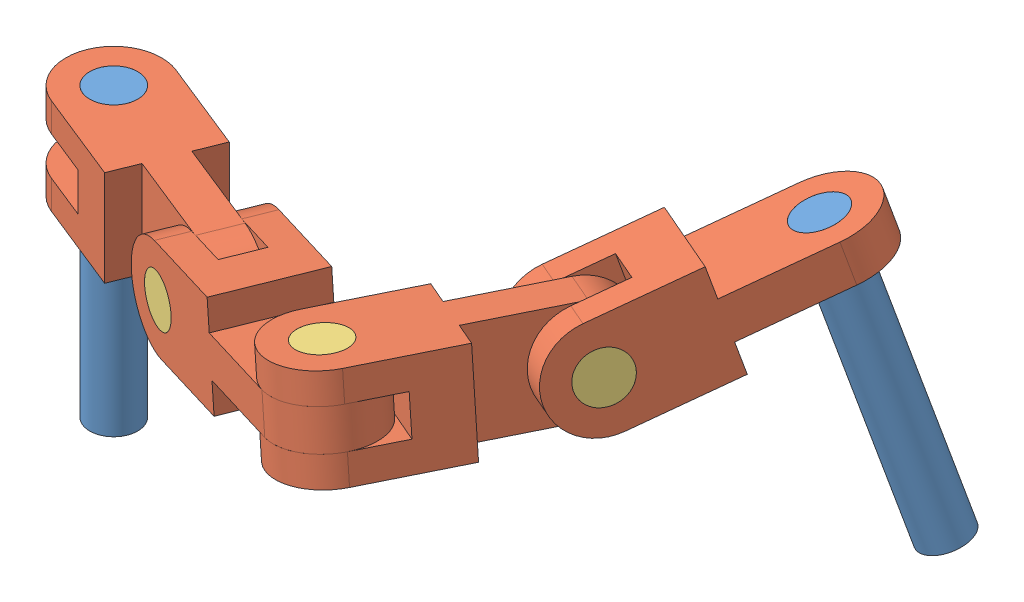
SolidWorks assembly E53, configuration Predeterminado. Lengths in mm.
Overall size (705.57 403.68 507.68).
9 component instances, 3 part files, 17 mates.
Components (placement in the parent):
- P53.1-1: P53.1 [Predeterminado] at origin size (50 300 50)
- P53.3-1: P53.3 [Predeterminado] at (239.4495 300 74.5917) x (-0.372606 0 0.92799) z (0 -1 0) size (100 300 100)
- P53.3-2: P53.3 [Predeterminado] at (436.6565 262.947 121.4462) x (-0.121657 0.991369 -0.048848) z (-0.372606 0 0.92799) size (100 300 100)
- P53.2-1: P53.2 [Predeterminado] at (204.2282 250 28.1217) x (0.835308 0.435629 0.335392) z (0.404259 -0.900126 0.162318) size (50 100 50)
- P53.3-3: P53.3 [Predeterminado] at (523.5158 324.1304 -273.228) x (-0.24251 0.949935 0.197009) z (0.880876 0.130517 0.454997) size (100 300 100)
- P53.3-4: P53.3 [Predeterminado] at (507.6559 232.3426 -62.3465) x (-0.880876 -0.130517 -0.454997) z (-0.121657 0.991369 -0.048848) size (100 300 100)
- P53.2-2: P53.2 [Predeterminado] at (375.6769 226.651 150.8416) x (-0.352723 -0.089181 -0.931468) z (0.927786 0.09609 -0.360528) size (50 100 50)
- P53.2-3: P53.2 [Predeterminado] at (417.0394 272.1586 -52.1811) x (0.466922 -0.397423 -0.789961) z (-0.077723 -0.908306 0.411021) size (50 100 50)
- P53.1-2: P53.1 [Predeterminado] at (610.2869 69.479 -258.2791) x (-0.281748 -0.26328 0.92266) z (-0.928336 -0.168247 -0.331491) size (50 300 50)
Mates (geometry in assembly coordinates):
- Coincidente1: coordinate: point of P53.1-1
- Concéntrica1: concentric anti-aligned: cylinder of P53.1-1 through (0 300 0) axis (0 -1 0) radius 25; cylinder of P53.3-1 through (0 200 0) axis (0 1 0) radius 25
- Coincidente2: coincident anti-aligned: circle of P53.1-1; circle of P53.3-1
- Coincidente3: coincident anti-aligned: plane of P53.3-1 through (100.2511 200 18.7008) normal (0.372606 0 -0.92799); plane of P53.3-2 through (429.1281 233.2059 150.7513) normal (-0.372606 0 0.92799)
- Coincidente4: coincident aligned: circle of P53.3-1; circle of P53.3-2
- Concéntrica2: concentric anti-aligned: cylinder of P53.3-1 through (215.4064 250 0.282) axis (-0.372606 0 0.92799) radius 25; cylinder of P53.2-1 through (166.9676 250 120.9207) axis (0.372606 0 -0.92799) radius 25
- Coincidente5: coincident aligned: circle of P53.3-2; circle of P53.2-1
- Concéntrica3: concentric anti-aligned: cylinder of P53.3-2 through (379.3266 196.9099 152.307) axis (-0.121657 0.991369 -0.048848) radius 25; cylinder of P53.2-2 through (363.5112 325.788 145.9568) axis (0.121657 -0.991369 0.048848) radius 25
- Coincidente13: coincident anti-aligned: plane of P53.3-2 through (261.3989 243.2824 158.8366) normal (0.121657 -0.991369 0.048848); plane of P53.3-4 through (530.4325 265.9992 -50.162) normal (-0.121657 0.991369 -0.048848)
- Coincidente16: coincident aligned: circle of P53.3-2; circle of P53.3-4
- Coincidente17: coincident aligned: circle of P53.3-4; circle of P53.2-2
- Coincidente18: coincident anti-aligned: plane of P53.3-3 through (557.2174 299.5478 -265.4883) normal (0.880876 0.130517 0.454997); plane of P53.3-4 through (460.2551 326.2589 -85.4312) normal (-0.880876 -0.130517 -0.454997)
- Coincidente19: coincident aligned: circle of P53.3-3; circle of P53.3-4
- Concéntrica4: concentric aligned: cylinder of P53.3-4 through (531.5533 289.1258 6.9685) axis (-0.880876 -0.130517 -0.454997) radius 25; cylinder of P53.2-3 through (505.127 285.2103 -6.6814) axis (-0.880876 -0.130517 -0.454997) radius 25
- Coincidente20: coincident aligned: circle of P53.3-3; circle of P53.2-3
- Concéntrica5: concentric anti-aligned: cylinder of P53.3-3 through (561.785 259.466 -218.8773) axis (-0.24251 0.949935 0.197009) radius 25; cylinder of P53.1-2 through (537.534 354.4595 -199.1764) axis (0.24251 -0.949935 -0.197009) radius 25
- Coincidente21: coincident aligned: circle of P53.3-3; circle of P53.1-2
